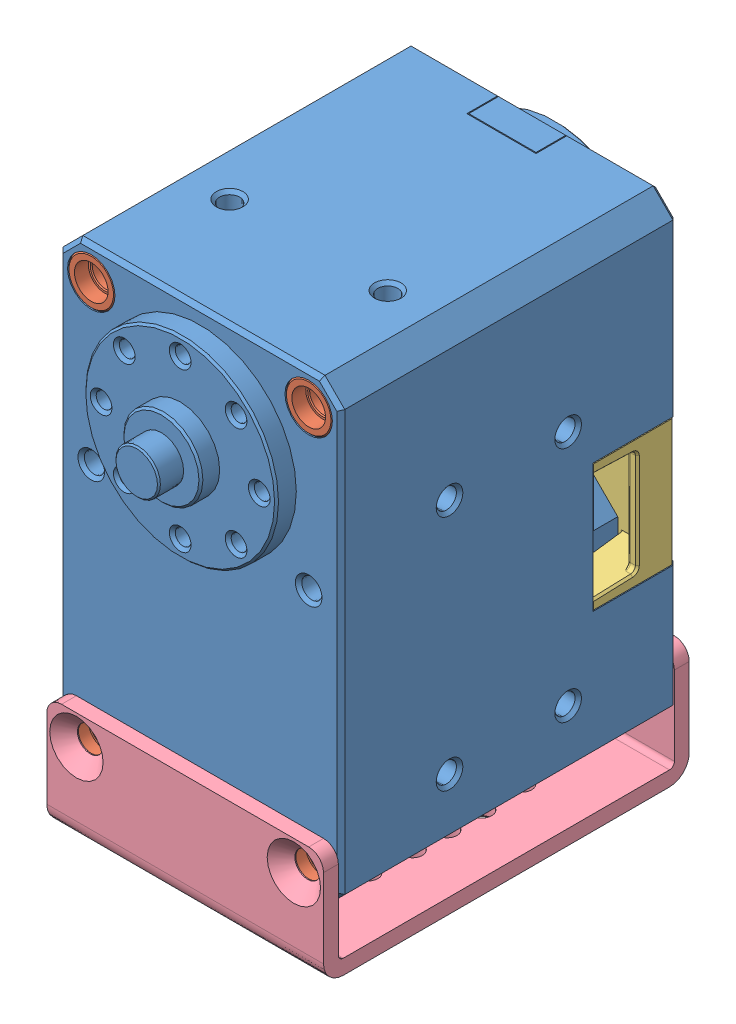
SolidWorks assembly link2, configuration 기본. Lengths in mm.
Overall size (28.5 51.75 42.4).
12 component instances, 4 part files, 2 mates.
Components (placement in the parent):
- x-430_idle-1: x-430_idle [기본] at (-8.4241 14.1369 44.3001) size (28.5 46.5 42.4)
  - X-430_IDLE-1: X-430_IDLE [기본] at origin size (28.5 46.5 42.4)
  - X-430_SPACER_RING-1: X-430_SPACER_RING [기본] at (11 8 14.2) x (-1 0 0) z (0 1 0) size (4.8 2.8 4.8)
  - X-430_SPACER_RING-2: X-430_SPACER_RING [기본] at (-11 8 14.2) x (-1 0 0) z (0 1 0) size (4.8 2.8 4.8)
  - X-430_SPACER_RING-3: X-430_SPACER_RING [기본] at (11 -32 14.2) x (-1 0 0) z (0 1 0) size (4.8 2.8 4.8)
  - X-430_SPACER_RING-4: X-430_SPACER_RING [기본] at (-11 -32 14.2) x (-1 0 0) z (0 1 0) size (4.8 2.8 4.8)
  - X-430_SPACER_RING-5: X-430_SPACER_RING [기본] at (-11 8 -14.2) x (1 0 0) z (0 1 0) size (4.8 2.8 4.8)
  - X-430_SPACER_RING-6: X-430_SPACER_RING [기본] at (11 8 -14.2) x (1 0 0) z (0 1 0) size (4.8 2.8 4.8)
  - X-430_SPACER_RING-7: X-430_SPACER_RING [기본] at (-11 -32 -14.2) x (1 0 0) z (0 1 0) size (4.8 2.8 4.8)
  - X-430_SPACER_RING-8: X-430_SPACER_RING [기본] at (11 -32 -14.2) x (1 0 0) z (0 1 0) size (4.8 2.8 4.8)
  - X-430_CVR_CABLE-1: X-430_CVR_CABLE [기본] at origin size (28.5 12.8 8.8)
- fr12_s102-1: fr12_s102 [기본] at (-8.4241 -6.8631 44.3001) x (0 0 -1) z (0 -1 0) size (37 28 11.5)
Mates (geometry in assembly coordinates):
- 너비2: width aligned: plane of fr12_s102-1 through (-22.4241 -24.3631 61.3001) normal (0 0 -1); plane of fr12_s102-1 through (-22.4241 -14.8631 27.3001) normal (0 0 1); plane of x-430_idle-1/X-430_IDLE-1 through (-8.4241 14.1369 27.3001) normal (0 0 -1); plane of x-430_idle-1/X-430_IDLE-1 through (-8.4241 14.1369 61.3001) normal (0 0 1)
- 동심4: concentric anti-aligned: circle of x-430_idle-1/X-430_SPACER_RING-4; circle of fr12_s102-1
